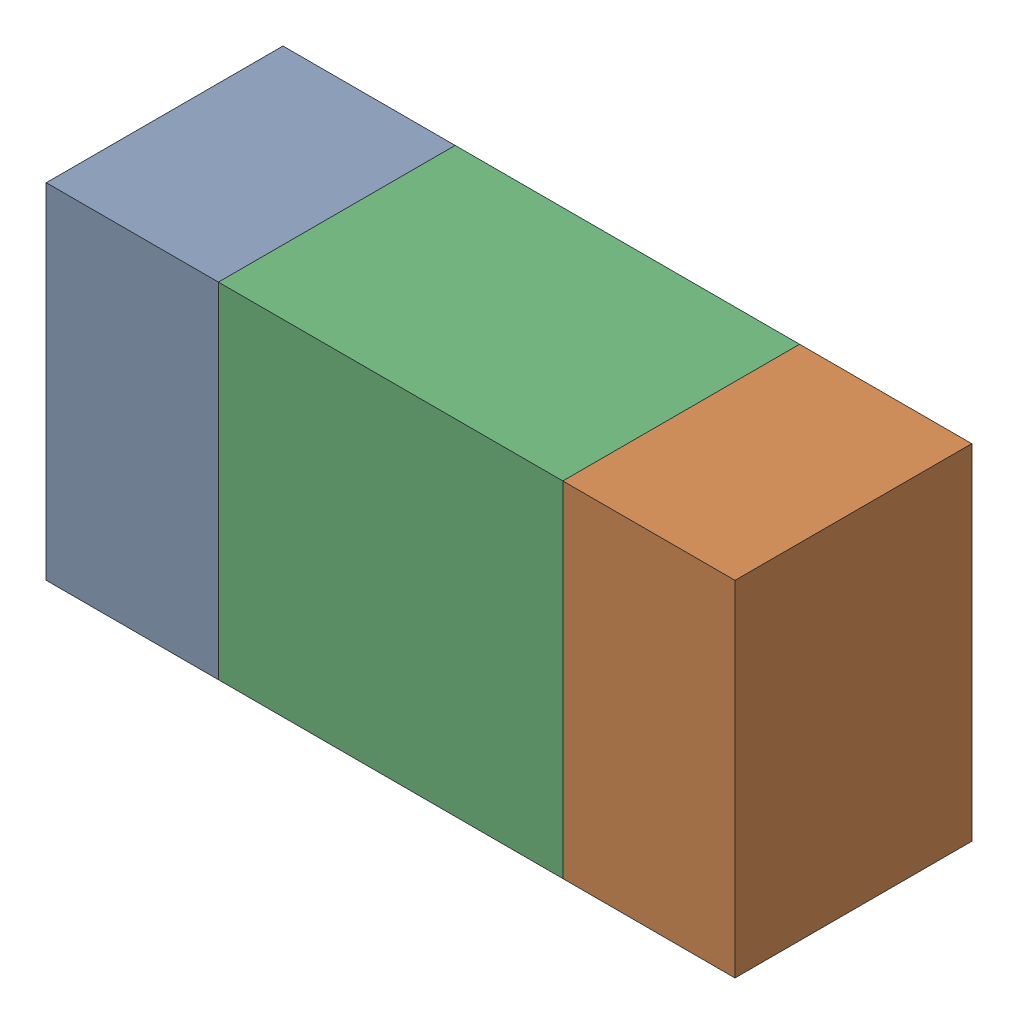
SolidWorks assembly R67, configuration ﾃﾞﾌｫﾙﾄ. Lengths in mm.
Overall size (1.6 0.8 0.55).
6 component instances, 2 part files, 0 mates.
Components (placement in the parent):
- 689261512-1: 689261512 [ﾃﾞﾌｫﾙﾄ] at (10.6501 54.4999 -1.7503) size (0.4 0.8 0.55)
  - Extruded_32-1: Extruded_32 [ﾃﾞﾌｫﾙﾄ] at origin size (0.4 0.8 0.55)
- 689261512-2: 689261512 [ﾃﾞﾌｫﾙﾄ] at (11.8501 54.4999 -1.7503) size (0.4 0.8 0.55)
  - Extruded_32-1: Extruded_32 [ﾃﾞﾌｫﾙﾄ] at origin size (0.4 0.8 0.55)
- 689261648-1: 689261648 [ﾃﾞﾌｫﾙﾄ] at (11.25 54.4999 -1.7503) size (0.8 0.8 0.55)
  - Extruded_33-1: Extruded_33 [ﾃﾞﾌｫﾙﾄ] at origin size (0.8 0.8 0.55)
